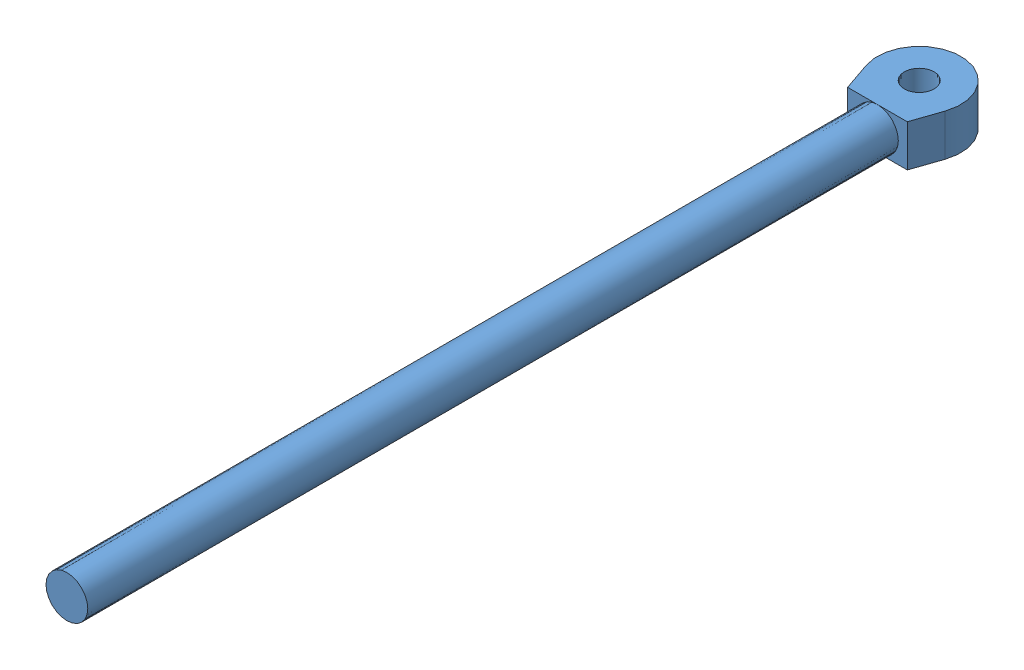
SolidWorks assembly hydraulic_cylinder_25CA, configuration Default. Lengths in mm.
Overall size (131.87 75 841).
2 component instances, 2 part files, 4 mates.
Components (placement in the parent):
- Cylinder_inside-1: Cylinder_inside [Default] at (0 0 664) x (0 -1 0) z (0 0 -1) size (35 70 749)
- Cylinder_outside-1: Cylinder_outside [Default] at origin size (131.87 75 756) (suppressed, hidden)
Mates (geometry in assembly coordinates):
- Concentric1: concentric anti-aligned: cylinder of Cylinder_inside-1 through (0 0 -15) axis (0 0 1) radius 17.5; cylinder of Cylinder_outside-1 through (0 0 664) axis (0 0 -1) radius 17.5
- Parallel1: parallel anti-aligned: plane of Cylinder_inside-1 through (0 -17.5 -50) normal (0 -1 0); plane of Cylinder_outside-1 through (-34.3693 15 756) normal (0 1 0)
- Coincident9: coordinate: point of Cylinder_outside-1
- LimitDistance1: limit distance = 0 mm anti-aligned: plane of Cylinder_inside-1 through (0 0 664) normal (0 0 1); plane of Cylinder_outside-1 through (0 0 664) normal (0 0 -1)
